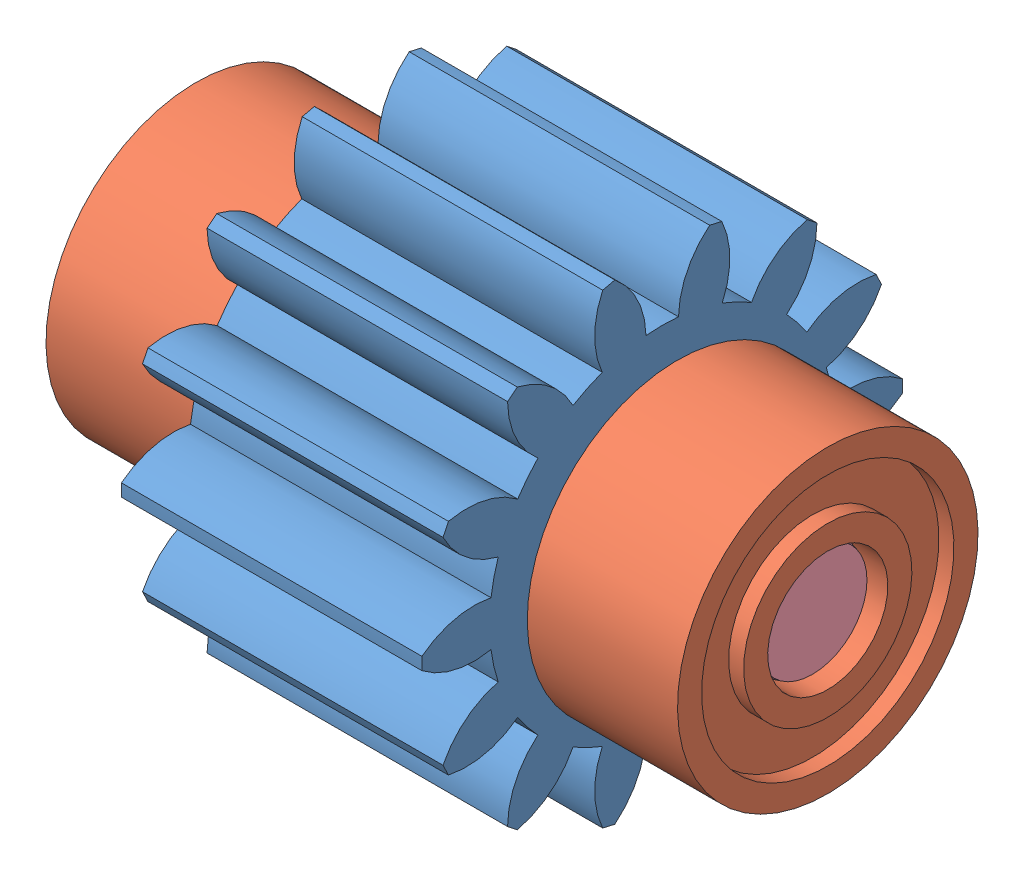
SolidWorks assembly Planet Gear Subassembly, configuration Default. Lengths in mm.
Overall size (10.51 7.84 8).
6 component instances, 4 part files, 9 mates.
Components (placement in the parent):
- planet gear 14T independent-1: planet gear 14T independent [Default] at origin size (5 7.84 8)
- MR63-2RS-1: MR63-2RS [Default] at (21.7032 4.3896 -8.2914) x (0 0.44755 0.894259) z (0 0.894259 -0.44755) size (5 2.5 5)
- MR63-2RS-2: MR63-2RS [Default] at (13.6952 4.3896 -8.2914) x (0 0.44755 0.894259) z (0 -0.894259 0.44755) size (5 2.5 5)
- 93574A161_18-8 STAINLESS STEEL SHIMS-1: 93574A161_18-8 STAINLESS STEEL SHIMS [93574A161] at (20.1992 4.3896 -8.2914) x (0 -0.319794 0.947487) z (0 0.947487 0.319794) size (3.89 0.25 3.89)
- 93574A161_18-8 STAINLESS STEEL SHIMS-2: 93574A161_18-8 STAINLESS STEEL SHIMS [93574A161] at (15.1992 4.3896 -8.2914) x (0 -0.319794 0.947487) z (0 -0.947487 -0.319794) size (3.89 0.25 3.89)
- 91585A221_METRIC 18-8 STAINLESS STEEL DOWEL PIN-1: 91585A221_METRIC 18-8 STAINLESS STEEL DOWEL PIN [91585A221] at (17.6992 4.3896 -8.2914) size (10 2 2)
Mates (geometry in assembly coordinates):
- Coincident1: coincident aligned: plane of planet gear 14T independent-1 through (0 0 0) normal (0 0 1)
- Coincident2: coincident aligned: plane of planet gear 14T independent-1 through (0 0 0) normal (0 1 0)
- Coincident3: coincident aligned: plane of planet gear 14T independent-1 through (0 0 0) normal (1 0 0)
- Concentric3: concentric anti-aligned: cylinder of planet gear 14T independent-1 through (15.1992 4.3896 -8.2914) axis (1 0 0) radius 1.05; cylinder of MR63-2RS-1 through (22.9532 4.3896 -8.2914) axis (-1 0 0) radius 1
- Coincident4: coincident anti-aligned: plane of planet gear 14T independent-1 through (20.1992 4.3896 -8.2914) normal (1 0 0); plane of 93574A161_18-8 STAINLESS STEEL SHIMS-1 through (20.1992 4.3896 -8.2914) normal (-1 0 0)
- Concentric4: concentric aligned: cylinder of planet gear 14T independent-1 through (15.1992 4.3896 -8.2914) axis (1 0 0) radius 1.05; cylinder of 93574A161_18-8 STAINLESS STEEL SHIMS-1 through (20.1992 4.3896 -8.2914) axis (1 0 0) radius 1.1176
- Coincident5: coincident anti-aligned: plane of MR63-2RS-1 through (20.4532 4.3896 -8.2914) normal (-1 0 0); plane of 93574A161_18-8 STAINLESS STEEL SHIMS-1 through (20.4532 4.3896 -8.2914) normal (1 0 0)
- Concentric6: concentric aligned: cylinder of planet gear 14T independent-1 through (15.1992 4.3896 -8.2914) axis (1 0 0) radius 1.05; cylinder of 91585A221_METRIC 18-8 STAINLESS STEEL DOWEL PIN-1 through (13.0492 4.3896 -8.2914) axis (1 0 0) radius 1
- Width1: width anti-aligned: plane of 91585A221_METRIC 18-8 STAINLESS STEEL DOWEL PIN-1 through (22.6992 4.3896 -8.2914) normal (1 0 0); plane of planet gear 14T independent-1 through (12.6992 4.3896 -8.2914) normal (-1 0 0); plane of 91585A221_METRIC 18-8 STAINLESS STEEL DOWEL PIN-1 through (15.1992 4.3896 -8.2914) normal (-1 0 0); plane of planet gear 14T independent-1 through (20.1992 4.3896 -8.2914) normal (1 0 0)
